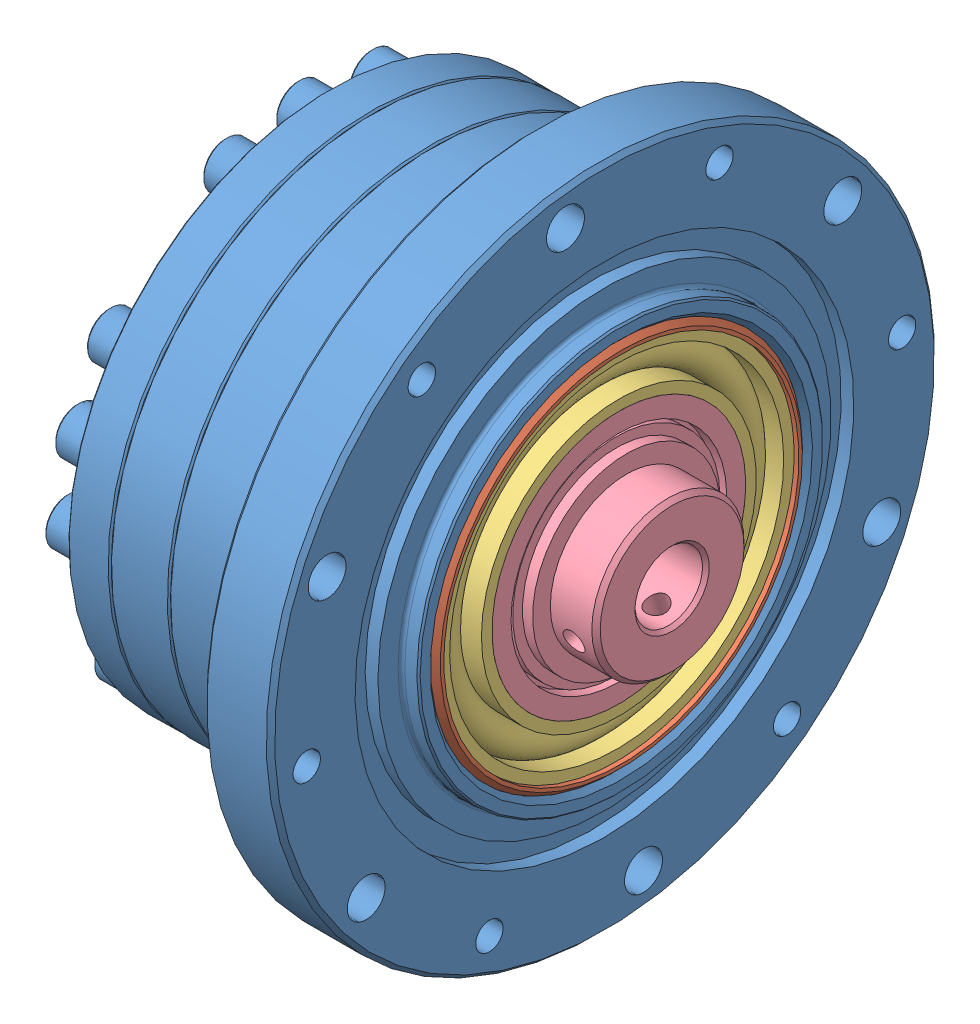
SolidWorks assembly CSF-17-100-2UH, configuration 기본. Lengths in mm.
Overall size (45 110.76 110.76).
4 component instances, 4 part files, 6 mates.
Components (placement in the parent):
- CSF-17-100-2UHCSF-17-2UH HOUSING_1-1: CSF-17-100-2UHCSF-17-2UH HOUSING_1 [기본] at (-0.6483 -0.4611 -8.7826) x (1 0 0) z (0 0.793661 0.608361) size (38.5 79 79)
- CSF-17-100-2UHCSF-17-2UH OUTPUT_2-1: CSF-17-100-2UHCSF-17-2UH OUTPUT_2 [기본] at (-0.6484 -0.4611 -8.7826) x (1 0 0) z (0 -0.998785 -0.049278) size (39 44 44)
- CSF-17-100-2UH17 WG BEARING_6-1: CSF-17-100-2UH17 WG BEARING_6 [기본] at (31.6367 -0.4611 -8.7826) x (1 0 0) z (0 -0.994573 0.104042) size (6.67 42 42)
- CSF-17-2A-R OLDHAM COUPLING.stp-1: CSF-17-2A-R OLDHAM COUPLING.stp [기본] at (44.3517 -0.4611 -8.7826) x (1 0 0) z (0 0.294148 -0.95576) size (19.5 37 37)
Mates (geometry in assembly coordinates):
- 거리1: distance = 0.5 mm aligned: plane of CSF-17-100-2UHCSF-17-2UH OUTPUT_2-1 through (-0.6483 -0.7321 -3.2892) normal (-1 0 0); plane of CSF-17-100-2UHCSF-17-2UH HOUSING_1-1 through (-0.1483 12.0103 -25.0526) normal (-1 0 0)
- 동심2: concentric aligned: cylinder of CSF-17-100-2UHCSF-17-2UH HOUSING_1-1 through (45.6683 -0.4611 -8.7826) axis (1 0 0) radius 31; cylinder of CSF-17-100-2UHCSF-17-2UH OUTPUT_2-1 through (43.5718 -0.4611 -8.7826) axis (1 0 0) radius 5
- 동심3: concentric anti-aligned: cylinder of CSF-17-100-2UHCSF-17-2UH HOUSING_1-1 through (45.6683 -0.4611 -8.7826) axis (1 0 0) radius 39.5; cylinder of CSF-17-100-2UH17 WG BEARING_6-1 through (31.6367 -0.4611 -8.7826) axis (-1 0 0) radius 15
- 거리2: distance = 1.7 mm aligned: plane of CSF-17-100-2UH17 WG BEARING_6-1 through (38.0517 1.0996 6.136) normal (1 0 0); plane of CSF-17-100-2UHCSF-17-2UH HOUSING_1-1 through (36.3517 23.265 -39.7353) normal (1 0 0)
- 동심4: concentric anti-aligned: cylinder of CSF-17-100-2UHCSF-17-2UH HOUSING_1-1 through (45.6683 -0.4611 -8.7826) axis (1 0 0) radius 39.5; cylinder of CSF-17-2A-R OLDHAM COUPLING.stp-1 through (44.3517 -0.4611 -8.7826) axis (-1 0 0) radius 15
- 거리3: distance = 8 mm aligned: plane of CSF-17-2A-R OLDHAM COUPLING.stp-1 through (44.3517 -0.4611 -8.7826) normal (1 0 0); plane of CSF-17-100-2UHCSF-17-2UH HOUSING_1-1 through (36.3517 23.265 -39.7353) normal (1 0 0)
